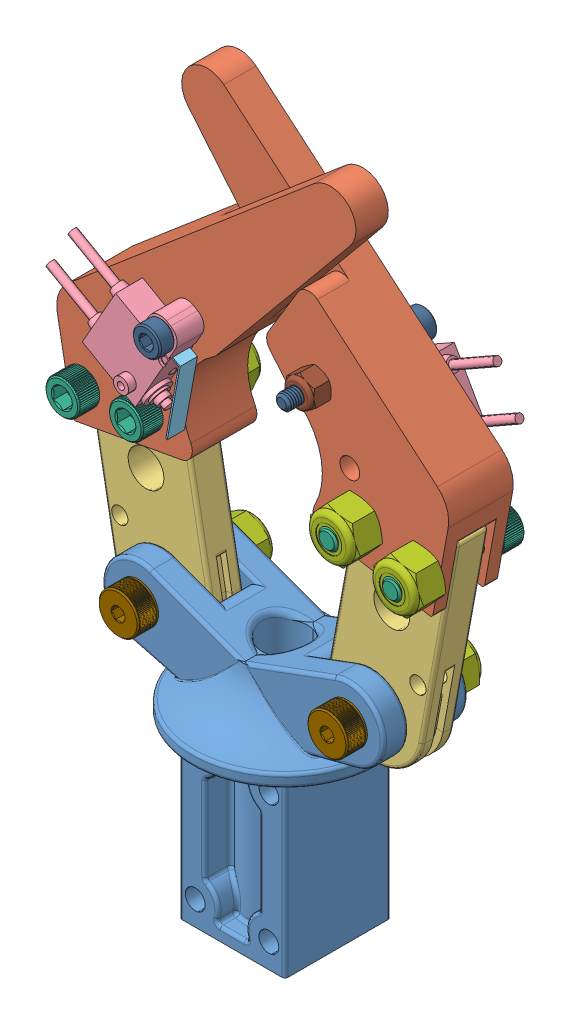
SolidWorks assembly MS-SA-0013f-03-03-Center Claw, configuration Default. Lengths in mm.
Overall size (88.94 137.16 36.64).
30 component instances, 12 part files, 43 mates.
Components (placement in the parent):
- MS-P-0064-03-02 Gripper Center Claw Piece-1: MS-P-0064-03-02 Gripper Center Claw Piece [Default] at (24.6401 45.6335 29.0361) x (0 0 -1) z (1 0 0) size (36.64 54.77 55.37)
- MS-P-0065-03-02 Gripper Claw v5-1: MS-P-0065-03-02 Gripper Claw v5 [Default] at (8.8403 72.5846 26.0516) x (0 0 -1) z (0.983605 0.180338 0) size (12.7 55.07 65.71)
- MS-P-0066-03 PVC Pipe-1: MS-P-0066-03 PVC Pipe [Default] at (24.3703 83.436 -41.6331) size (25.4 25.4 127) (hidden)
- MS-P-0067-03-02 Gripper Claw Base-4: MS-P-0067-03-02 Gripper Claw Base [Default] at (4.0978 45.6335 29.2266) x (-0.983605 -0.180338 0) z (0 0 -1) size (19.05 47.62 6.35)
- MS-C-0034-Gripper-Limit-Switch-1: MS-C-0034-Gripper-Limit-Switch [Default] at (6.3641 86.548 36.2116) x (0.494102 0.869404 0) z (0 0 -1) size (18.87 29.8 8.3)
  - D2HW_C262M_BASE-1: D2HW_C262M_BASE [Default] at origin size (18.5 26.81 8.3)
  - D2HW_C262M_ACTUATOR-1: D2HW_C262M_ACTUATOR [Default] at (10 3 -2.65) size (13.32 6.3 3.4)
- MS-P-0067-03-02 Gripper Claw Base-6: MS-P-0067-03-02 Gripper Claw Base [Default] at (45.1823 45.6335 28.8456) x (0.983605 -0.180338 0) z (0 0 1) size (19.05 47.62 6.35)
- MS-P-0065-03-02 Gripper Claw v5-4: MS-P-0065-03-02 Gripper Claw v5 [Default] at (40.4399 72.5846 32.0206) x (0 0 1) z (-0.983605 0.180338 0) size (12.7 55.07 65.71)
- 92196A197_18-8 STAINLESS STEEL SOCKET HEAD SCREW-1: 92196A197_18-8 STAINLESS STEEL SOCKET HEAD SCREW [92196A197] at (-7.9196 75.9676 17.1616) x (-0.997184 -0.074988 0) z (0 0 -1) size (6.85 6.85 23.75)
- 92196A197_18-8 STAINLESS STEEL SOCKET HEAD SCREW-2: 92196A197_18-8 STAINLESS STEEL SOCKET HEAD SCREW [92196A197] at (4.5722 78.2579 17.1616) x (-0.997184 -0.074988 0) z (0 0 -1) size (6.85 6.85 23.75)
- 90631A009_LOW-STRENGTH STEEL NYLON-INSERT LOCKNUT-1: 90631A009_LOW-STRENGTH STEEL NYLON-INSERT LOCKNUT [90631A009] at (-7.9196 75.9676 23.5116) x (0.949851 -0.312702 0) z (0.312702 0.949851 0) size (8.73 6.09 10.08)
- 90631A009_LOW-STRENGTH STEEL NYLON-INSERT LOCKNUT-2: 90631A009_LOW-STRENGTH STEEL NYLON-INSERT LOCKNUT [90631A009] at (4.5722 78.2579 23.5116) x (0.951403 -0.307949 0) z (0.307949 0.951403 0) size (8.73 6.09 10.08)
- 90631A009_LOW-STRENGTH STEEL NYLON-INSERT LOCKNUT-3: 90631A009_LOW-STRENGTH STEEL NYLON-INSERT LOCKNUT [90631A009] at (44.7079 78.2579 34.5606) x (-0.951403 -0.307949 0) z (-0.307949 0.951403 0) size (8.73 6.09 10.08)
- 90631A009_LOW-STRENGTH STEEL NYLON-INSERT LOCKNUT-4: 90631A009_LOW-STRENGTH STEEL NYLON-INSERT LOCKNUT [90631A009] at (57.1997 75.9676 34.5606) x (-0.949851 -0.312702 0) z (-0.312702 0.949851 0) size (8.73 6.09 10.08)
- 92196A197_18-8 STAINLESS STEEL SOCKET HEAD SCREW-3: 92196A197_18-8 STAINLESS STEEL SOCKET HEAD SCREW [92196A197] at (44.7079 78.2579 40.9106) x (0.997184 -0.074988 0) z (0 0 1) size (6.85 6.85 23.75)
- 92196A197_18-8 STAINLESS STEEL SOCKET HEAD SCREW-4: 92196A197_18-8 STAINLESS STEEL SOCKET HEAD SCREW [92196A197] at (57.1997 75.9676 40.9106) x (0.997184 -0.074988 0) z (0 0 1) size (6.85 6.85 23.75)
- 6389K300_LIGHT DUTY DRY-RUNNING SLEEVE BEARING-1: 6389K300_LIGHT DUTY DRY-RUNNING SLEEVE BEARING [6389K3] at (4.0978 45.6335 29.2266) x (-0.495857 0.868404 0) z (0 0 1) size (7.94 7.94 6.35)
- 6389K300_LIGHT DUTY DRY-RUNNING SLEEVE BEARING-2: 6389K300_LIGHT DUTY DRY-RUNNING SLEEVE BEARING [6389K3] at (45.1823 45.6335 28.8456) x (-0.984867 0.173311 0) z (0 0 -1) size (7.94 7.94 6.35)
- 90311A137_316 STAINLESS STEEL THREAD-LOCKING SHOULDER SCREW-1: 90311A137_316 STAINLESS STEEL THREAD-LOCKING SHOULDER SCREW [90311A137] at (4.0978 45.6335 41.3234) x (-0.084946 0.996386 0) z (0 0 1) size (7.94 7.94 25.05)
- 90311A137_316 STAINLESS STEEL THREAD-LOCKING SHOULDER SCREW-2: 90311A137_316 STAINLESS STEEL THREAD-LOCKING SHOULDER SCREW [90311A137] at (45.1823 45.6335 41.3234) x (-0.241851 0.970313 0) z (0 0 1) size (7.94 7.94 25.05)
- 90631A009_LOW-STRENGTH STEEL NYLON-INSERT LOCKNUT-5: 90631A009_LOW-STRENGTH STEEL NYLON-INSERT LOCKNUT [90631A009] at (4.0978 45.6335 20.7176) x (0.999998 -0.001774 0) z (0.001774 0.999998 0) size (8.73 6.09 10.08)
- 90631A009_LOW-STRENGTH STEEL NYLON-INSERT LOCKNUT-7: 90631A009_LOW-STRENGTH STEEL NYLON-INSERT LOCKNUT [90631A009] at (45.1823 45.6335 20.7176) x (0.98763 0.156801 0) z (-0.156801 0.98763 0) size (8.73 6.09 10.08)
- 91292A020_TYPE 18-8 SS SOCKET HEAD CAP SCREW-1: 91292A020_TYPE 18-8 SS SOCKET HEAD CAP SCREW [91292A020] at (12.7874 97.8502 16.5116) x (0.086557 -0.996247 0) z (0 0 -1) size (5.5 5.5 28.26)
- 93625A100_18-8 STAINLESS STEEL NYLON-INSERT LOCKNUT-1: 93625A100_18-8 STAINLESS STEEL NYLON-INSERT LOCKNUT [93625A100] at (12.7874 97.8502 23.5116) x (-0.084946 0.996386 0) z (-0.996386 -0.084946 0) size (5.5 4.19 6.35)
- 93625A100_18-8 STAINLESS STEEL NYLON-INSERT LOCKNUT-2: 93625A100_18-8 STAINLESS STEEL NYLON-INSERT LOCKNUT [93625A100] at (36.4927 97.8502 34.5606) x (0.995999 0.089365 0) z (0.089365 -0.995999 0) size (5.5 4.19 6.35)
- 91292A020_TYPE 18-8 SS SOCKET HEAD CAP SCREW-2: 91292A020_TYPE 18-8 SS SOCKET HEAD CAP SCREW [91292A020] at (36.4927 97.8502 41.5606) x (-0.996142 -0.087755 0) z (0 0 1) size (5.5 5.5 28.26)
- MS-C-0034-Gripper-Limit-Switch-2: MS-C-0034-Gripper-Limit-Switch [Default] at (42.916 86.548 21.8606) x (-0.494102 0.869404 0) z (0 0 1) size (18.87 29.8 8.3)
  - D2HW_C262M_BASE-1: D2HW_C262M_BASE [Default] at origin size (18.5 26.81 8.3)
  - D2HW_C262M_ACTUATOR-1: D2HW_C262M_ACTUATOR [Default] at (10 3 -2.65) size (13.32 6.3 3.4)
Mates (geometry in assembly coordinates):
- Concentric1: concentric anti-aligned: circle of MS-P-0064-03-02 Gripper Center Claw Piece-1; circle of MS-P-0067-03-02 Gripper Claw Base-4
- Coincident10: coincident anti-aligned: plane of MS-P-0064-03-02 Gripper Center Claw Piece-1 through (24.6401 45.6335 32.4016) normal (0 0 -1); plane of MS-P-0067-03-02 Gripper Claw Base-4 through (4.0978 45.6335 32.4016) normal (0 0 1)
- Concentric2: concentric anti-aligned: circle of MS-P-0065-03-02 Gripper Claw v5-1; circle of MS-P-0067-03-02 Gripper Claw Base-4
- Concentric3: concentric anti-aligned: circle of MS-P-0065-03-02 Gripper Claw v5-1; circle of MS-P-0067-03-02 Gripper Claw Base-4
- Coincident15: coincident anti-aligned: plane of MS-P-0065-03-02 Gripper Claw v5-1 through (8.8403 72.5846 26.0516) normal (0 0 1); plane of MS-P-0067-03-02 Gripper Claw Base-4 through (4.0978 45.6335 26.0516) normal (0 0 -1)
- Concentric4: concentric aligned: circle of D2HW_C262M-1/D2HW_C262M_BASE-1; cylinder of MS-P-0065-03-02 Gripper Claw v5-1 through (6.3641 86.548 36.2116) axis (0 0 -1) radius 1.95
- Coincident16: coincident anti-aligned: plane of MS-P-0065-03-02 Gripper Claw v5-1 through (24.7207 82.8632 36.2116) normal (0 0 1); plane of MS-C-0034-Gripper-Limit-Switch-1/D2HW_C262M_BASE-1 through (1.5771 86.2204 36.2116) normal (0 0 -1)
- Concentric5: concentric aligned: cylinder of MS-C-0034-Gripper-Limit-Switch-1/D2HW_C262M_BASE-1 through (12.7874 97.8502 41.5117) axis (0 0 -1) radius 1.65; cylinder of MS-P-0065-03-02 Gripper Claw v5-1 through (12.7874 97.8502 36.2116) axis (0 0 -1) radius 1.95
- LimitAngle1: limit planar angle = 0.18133 rad aligned: plane of MS-P-0067-03-02 Gripper Claw Base-4 through (-5.271 43.9158 26.0516) normal (-0.983605 -0.180338 0); plane of MS-P-0064-03-02 Gripper Center Claw Piece-1 through (14.2261 -1.9915 29.0361) normal (-1 0 0)
- Coincident17: coincident anti-aligned: plane of MS-P-0065-03-02 Gripper Claw v5-1 through (24.7207 82.8632 36.2116) normal (0 0 1); plane of 92196A197_18-8 STAINLESS STEEL SOCKET HEAD SCREW-1 through (-7.9196 75.9676 36.2116) normal (0 0 -1)
- Concentric6: concentric aligned: circle of MS-P-0065-03-02 Gripper Claw v5-1; circle of 92196A197_18-8 STAINLESS STEEL SOCKET HEAD SCREW-1
- Coincident18: coincident anti-aligned: plane of MS-P-0065-03-02 Gripper Claw v5-1 through (24.7207 82.8632 36.2116) normal (0 0 1); plane of 92196A197_18-8 STAINLESS STEEL SOCKET HEAD SCREW-2 through (4.5722 78.2579 36.2116) normal (0 0 -1)
- Concentric7: concentric aligned: circle of MS-P-0065-03-02 Gripper Claw v5-1; circle of 92196A197_18-8 STAINLESS STEEL SOCKET HEAD SCREW-2
- Coincident19: coincident anti-aligned: plane of MS-P-0065-03-02 Gripper Claw v5-1 through (8.8403 72.5846 23.5116) normal (0 0 -1); plane of 90631A009_LOW-STRENGTH STEEL NYLON-INSERT LOCKNUT-1 through (-14.4308 70.1505 23.5116) normal (0 0 1)
- Concentric8: concentric anti-aligned: circle of MS-P-0065-03-02 Gripper Claw v5-1; circle of 90631A009_LOW-STRENGTH STEEL NYLON-INSERT LOCKNUT-1
- Coincident21: coincident anti-aligned: plane of MS-P-0065-03-02 Gripper Claw v5-1 through (8.8403 72.5846 23.5116) normal (0 0 -1); plane of 90631A009_LOW-STRENGTH STEEL NYLON-INSERT LOCKNUT-2 through (-1.9099 72.4083 23.5116) normal (0 0 1)
- Concentric9: concentric aligned: circle of MS-P-0065-03-02 Gripper Claw v5-1; circle of 90631A009_LOW-STRENGTH STEEL NYLON-INSERT LOCKNUT-2
- Concentric10: concentric aligned: circle of MS-P-0064-03-02 Gripper Center Claw Piece-1; circle of 6389K300_LIGHT DUTY DRY-RUNNING SLEEVE BEARING-1
- Width1: width aligned: plane of MS-P-0067-03-02 Gripper Claw Base-4 through (4.0978 45.6335 32.4016) normal (0 0 1); plane of 6389K300_LIGHT DUTY DRY-RUNNING SLEEVE BEARING-1 through (4.0978 45.6335 26.0516) normal (0 0 -1); plane of MS-P-0067-03-02 Gripper Claw Base-4 through (4.0978 45.6335 32.4016) normal (0 0 1); plane of 6389K300_LIGHT DUTY DRY-RUNNING SLEEVE BEARING-1 through (4.0978 45.6335 26.0516) normal (0 0 -1)
- Concentric11: concentric aligned: circle of MS-P-0064-03-02 Gripper Center Claw Piece-1; circle of 6389K300_LIGHT DUTY DRY-RUNNING SLEEVE BEARING-2
- Width2: width aligned: plane of MS-P-0067-03-02 Gripper Claw Base-6 through (45.1823 45.6335 25.6706) normal (0 0 -1); plane of 6389K300_LIGHT DUTY DRY-RUNNING SLEEVE BEARING-2 through (45.1823 45.6335 32.0206) normal (0 0 1); plane of MS-P-0067-03-02 Gripper Claw Base-6 through (45.1823 45.6335 25.6706) normal (0 0 -1); plane of 6389K300_LIGHT DUTY DRY-RUNNING SLEEVE BEARING-2 through (45.1823 45.6335 32.0206) normal (0 0 1)
- Coincident11: coincident anti-aligned: plane of MS-P-0064-03-02 Gripper Center Claw Piece-1 through (4.0978 45.6335 37.3546) normal (0 0 1); plane of 90311A137_316 STAINLESS STEEL THREAD-LOCKING SHOULDER SCREW-1 through (8.0522 45.9706 37.3546) normal (0 0 -1)
- Concentric12: concentric aligned: circle of MS-P-0064-03-02 Gripper Center Claw Piece-1; circle of 90311A137_316 STAINLESS STEEL THREAD-LOCKING SHOULDER SCREW-1
- Coincident12: coincident anti-aligned: plane of MS-P-0064-03-02 Gripper Center Claw Piece-1 through (45.1823 45.6335 37.3546) normal (0 0 1); plane of 90311A137_316 STAINLESS STEEL THREAD-LOCKING SHOULDER SCREW-2 through (49.0332 46.5933 37.3546) normal (0 0 -1)
- Concentric13: concentric anti-aligned: circle of MS-P-0064-03-02 Gripper Center Claw Piece-1; circle of 90311A137_316 STAINLESS STEEL THREAD-LOCKING SHOULDER SCREW-2
- Coincident22: coincident anti-aligned: plane of MS-P-0064-03-02 Gripper Center Claw Piece-1 through (4.0978 45.6335 20.7176) normal (0 0 -1); plane of 90631A009_LOW-STRENGTH STEEL NYLON-INSERT LOCKNUT-5 through (-0.2812 38.0798 20.7176) normal (0 0 1)
- Concentric14: concentric aligned: circle of MS-P-0064-03-02 Gripper Center Claw Piece-1; circle of 90631A009_LOW-STRENGTH STEEL NYLON-INSERT LOCKNUT-5
- Coincident24: coincident anti-aligned: plane of MS-P-0064-03-02 Gripper Center Claw Piece-1 through (45.1823 45.6335 20.7176) normal (0 0 -1); plane of 90631A009_LOW-STRENGTH STEEL NYLON-INSERT LOCKNUT-7 through (42.0563 37.481 20.7176) normal (0 0 1)
- Concentric15: concentric anti-aligned: circle of MS-P-0064-03-02 Gripper Center Claw Piece-1; circle of 90631A009_LOW-STRENGTH STEEL NYLON-INSERT LOCKNUT-7
- Coincident13: coincident anti-aligned: plane of MS-C-0034-Gripper-Limit-Switch-1/D2HW_C262M_BASE-1 through (1.5771 86.2204 41.5116) normal (0 0 1); plane of 91292A020_TYPE 18-8 SS SOCKET HEAD CAP SCREW-1 through (12.7874 97.8502 41.5116) normal (0 0 -1)
- Concentric16: concentric anti-aligned: circle of MS-P-0065-03-02 Gripper Claw v5-1; circle of 91292A020_TYPE 18-8 SS SOCKET HEAD CAP SCREW-1
- Coincident14: coincident anti-aligned: plane of MS-P-0065-03-02 Gripper Claw v5-1 through (8.8403 72.5846 23.5116) normal (0 0 -1); plane of 93625A100_18-8 STAINLESS STEEL NYLON-INSERT LOCKNUT-1 through (12.3202 103.3303 23.5116) normal (0 0 1)
- Concentric17: concentric aligned: circle of MS-P-0065-03-02 Gripper Claw v5-1; circle of 93625A100_18-8 STAINLESS STEEL NYLON-INSERT LOCKNUT-1
- Coincident25: coincident anti-aligned: plane of 91292A020_TYPE 18-8 SS SOCKET HEAD CAP SCREW-2 through (36.4927 97.8502 16.5606) normal (0 0 1); plane of MS-C-0034-Gripper-Limit-Switch-2/D2HW_C262M_BASE-1 through (47.703 86.2204 16.5606) normal (0 0 -1)
- Concentric18: concentric aligned: circle of MS-P-0065-03-02 Gripper Claw v5-4; circle of MS-C-0034-Gripper-Limit-Switch-2/D2HW_C262M_BASE-1
- Coincident26: coincident anti-aligned: plane of MS-P-0065-03-02 Gripper Claw v5-4 through (24.5594 82.8632 21.8606) normal (0 0 -1); plane of MS-C-0034-Gripper-Limit-Switch-2/D2HW_C262M_BASE-1 through (47.703 86.2204 21.8606) normal (0 0 1)
- Concentric19: concentric aligned: circle of MS-P-0065-03-02 Gripper Claw v5-4; cylinder of MS-C-0034-Gripper-Limit-Switch-2/D2HW_C262M_BASE-1 through (36.4927 97.8502 16.5606) axis (0 0 1) radius 1.65
- Concentric20: concentric anti-aligned: cylinder of MS-P-0065-03-02 Gripper Claw v5-4 through (36.4927 97.8502 21.8606) axis (0 0 1) radius 1.95; circle of 91292A020_TYPE 18-8 SS SOCKET HEAD CAP SCREW-2
- Coincident27: coincident anti-aligned: plane of MS-P-0065-03-02 Gripper Claw v5-4 through (40.4399 72.5846 34.5606) normal (0 0 1); plane of 93625A100_18-8 STAINLESS STEEL NYLON-INSERT LOCKNUT-2 through (41.9707 98.3417 34.5606) normal (0 0 -1)
- Concentric21: concentric aligned: circle of MS-P-0065-03-02 Gripper Claw v5-4; circle of 93625A100_18-8 STAINLESS STEEL NYLON-INSERT LOCKNUT-2
- Concentric23: concentric anti-aligned: circle of 93625A100_18-8 STAINLESS STEEL NYLON-INSERT LOCKNUT-2; circle of 91292A020_TYPE 18-8 SS SOCKET HEAD CAP SCREW-2
- Concentric24: concentric aligned: circle of MS-P-0065-03-02 Gripper Claw v5-4; circle of MS-C-0034-Gripper-Limit-Switch-2/D2HW_C262M_BASE-1
- Concentric25: concentric aligned: circle of MS-P-0065-03-02 Gripper Claw v5-4; circle of 91292A020_TYPE 18-8 SS SOCKET HEAD CAP SCREW-2
